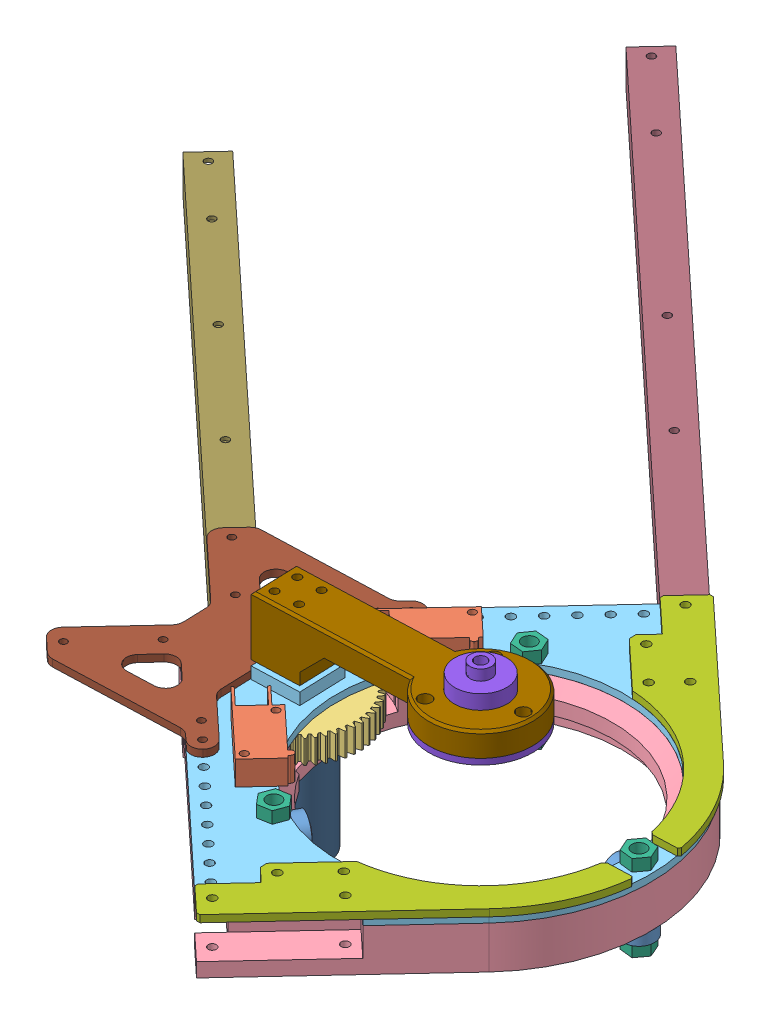
SolidWorks assembly steer_base, configuration ﾃﾞﾌｫﾙﾄ. Lengths in mm.
Overall size (394.9 104.1 424.52).
25 component instances, 13 part files, 51 mates.
Components (placement in the parent):
- Copy of bear_3^steer_base-1: Copy of bear_3^steer_base [ﾃﾞﾌｫﾙﾄ] at (64.7019 -27.57 57.0296) x (-0.998139 0 0.060972) z (0 1 0) size (13 13 5) (virtual)
- Copy of bear_3^steer_base-2: Copy of bear_3^steer_base [ﾃﾞﾌｫﾙﾄ] at (164.1261 -27.57 109.8486) x (-0.435507 0 0.900185) z (0 1 0) size (13 13 5) (virtual)
- Copy of LS^steer_base-1: Copy of LS^steer_base [ﾃﾞﾌｫﾙﾄ] at (50.8347 9.23 168.1143) x (-0.731598 0 -0.681736) z (0 -1 0) size (37.8 18.1 10.3) (virtual)
- Copy of bear_3^steer_base-3: Copy of bear_3^steer_base [ﾃﾞﾌｫﾙﾄ] at (67.3531 -9.07 61.2689) x (-0.432819 -0.859886 0.270672) z (0.530223 0 0.847858) size (13 13 5) (virtual)
- Copy of steer_gear_1^steer_base-1: Copy of steer_gear_1^steer_base [ﾃﾞﾌｫﾙﾄ] at (-26.2181 -27.57 -51.6068) x (0.883116 0 0.469155) z (-0.469155 0 0.883116) size (52 10 52.13) (virtual)
- Copy of base^steer_base-1: Copy of base^steer_base [ﾃﾞﾌｫﾙﾄ] at (99.1665 -14.07 112.1404) x (0.731598 0 0.681736) z (0 1 0) size (160 160 19.28) (virtual)
- Copy of bear_3^steer_base-4: Copy of bear_3^steer_base [ﾃﾞﾌｫﾙﾄ] at (154.1323 -9.07 110.2012) x (0.032581 0.382218 0.923498) z (0.999378 0 -0.035258) size (13 13 5) (virtual)
- Copy of bear_3^steer_base-5: Copy of bear_3^steer_base [ﾃﾞﾌｫﾙﾄ] at (73.363 -9.07 160.7117) x (-0.532711 -0.797577 -0.283002) z (-0.469155 0 0.883116) size (13 13 5) (virtual)
- Copy of bear_3^steer_base-6: Copy of bear_3^steer_base [ﾃﾞﾌｫﾙﾄ] at (68.6714 -27.57 169.5429) x (-0.435507 0 0.900185) z (0 1 0) size (13 13 5) (virtual)
- Copy of base_cover^steer_base-1: Copy of base_cover^steer_base [ﾃﾞﾌｫﾙﾄ] at (99.1665 -4.07 112.1404) x (0.731598 0 0.681736) z (0 1 0) size (160 160 8) (virtual)
- Copy of LS^steer_base-2: Copy of LS^steer_base [ﾃﾞﾌｫﾙﾄ] at (47.0102 -1.07 59.7116) x (-0.681736 0 0.731598) z (0 1 0) size (37.8 18.1 10.3) (virtual)
- Copy of M6_nut^steer_base-1: Copy of M6_nut^steer_base [ﾃﾞﾌｫﾙﾄ] at (164.1261 -1.07 109.8486) x (0.398878 0 0.917004) z (0 1 0) size (11.55 10 5) (virtual)
- Copy of bamper^steer_base-1: Copy of bamper^steer_base [ﾃﾞﾌｫﾙﾄ] at (99.1665 -1.07 112.1404) x (0.731598 0 0.681736) z (0 1 0) size (26 131.43 3) (virtual)
- Copy of bamper^steer_base-2: Copy of bamper^steer_base [ﾃﾞﾌｫﾙﾄ] at (99.1665 1.93 112.1404) x (0.681736 0 -0.731598) z (0 -1 0) size (26 131.43 3) (virtual)
- Copy of slip_ring^steer_base-1: Copy of slip_ring^steer_base [ﾃﾞﾌｫﾙﾄ] at (99.1665 13.73 112.1404) x (0.999378 0 -0.035258) z (0 1 0) size (44 44 33) (virtual)
- Copy of slip_ring_base^steer_base-1: Copy of slip_ring_base^steer_base [ﾃﾞﾌｫﾙﾄ] at (99.1665 21.23 112.1404) x (0.999378 0 -0.035258) z (0 1 0) size (107 44 25) (virtual)
- Copy of M6_nut^steer_base-2: Copy of M6_nut^steer_base [ﾃﾞﾌｫﾙﾄ] at (68.6714 -1.07 169.5429) x (0.642883 0 0.765964) z (0 1 0) size (11.55 10 5) (virtual)
- Copy of M6_nut^steer_base-3: Copy of M6_nut^steer_base [ﾃﾞﾌｫﾙﾄ] at (164.1261 -32.57 109.8486) x (0.398878 0 0.917004) z (0 1 0) size (11.55 10 5) (virtual)
- Copy of M6_nut^steer_base-4: Copy of M6_nut^steer_base [ﾃﾞﾌｫﾙﾄ] at (68.6714 -32.57 169.5429) x (0.398878 0 0.917004) z (0 1 0) size (11.55 10 5) (virtual)
- Copy of M6_nut^steer_base-5: Copy of M6_nut^steer_base [ﾃﾞﾌｫﾙﾄ] at (64.7019 -32.57 57.0296) x (0.398878 0 0.917004) z (0 1 0) size (11.55 10 5) (virtual)
- Copy of M6_nut^steer_base-6: Copy of M6_nut^steer_base [ﾃﾞﾌｫﾙﾄ] at (64.7019 -1.07 57.0296) x (0.995843 0 0.091089) z (0 1 0) size (11.55 10 5) (virtual)
- Copy of M2006^steer_base-1: Copy of M2006^steer_base [ﾃﾞﾌｫﾙﾄ] at (24.7128 -18.57 114.7671) x (0.883116 0 0.469155) z (0 -1 0) size (24.4 24.4 60.8) (virtual)
- Copy of Copy of joint2^steer_base-1: Copy of Copy of joint2^steer_base [ﾃﾞﾌｫﾙﾄ] at (13.9109 -1.07 115.1482) x (-0.731598 0 -0.681736) z (0.681736 0 -0.731598) size (115 3 115) (virtual)
- Copy of Copy of Copy of Copy of pipe180x10^steer_base-1: Copy of Copy of Copy of Copy of pipe180x10^steer_base [ﾃﾞﾌｫﾙﾄ] at (-216.7194 54.9921 -75.6002) x (0 -1 0) z (0.681736 0 -0.731598) size (15 240 15) (virtual)
- Copy of pipe280x15^steer_base-1: Copy of pipe280x15^steer_base [ﾃﾞﾌｫﾙﾄ] at (-126.3246 -16.07 -99.2643) x (0.681736 0 -0.731598) z (0 1 0) size (15 340 15) (virtual)
Mates (geometry in assembly coordinates):
- 一致170: coincident aligned: plane of Copy of bear_3^Assem2_swerve_unit-1 through (64.7019 -22.57 57.0296) normal (0 1 0); plane of Copy of bear_3^Assem2_swerve_unit-2 through (164.1261 -22.57 109.8486) normal (0 1 0)
- 同心円128: concentric anti-aligned: cylinder of Copy of bear_3^Assem2_swerve_unit-1 through (64.7019 -22.57 57.0296) axis (0 -1 0) radius 3; cylinder of Copy of base^steer_base-1 through (64.7019 -22.07 57.0296) axis (0 1 0) radius 3.15
- 一致312: coincident anti-aligned: plane of Copy of bear_3^Assem2_swerve_unit-1 through (64.7019 -27.57 57.0296) normal (0 -1 0); plane of Copy of M6_nut^Assem2_swerve_unit-5 through (64.7019 -27.57 57.0296) normal (0 1 0)
- 同心円166: concentric aligned: cylinder of Copy of bear_3^Assem2_swerve_unit-1 through (64.7019 -22.57 57.0296) axis (0 -1 0) radius 3; cylinder of Copy of M6_nut^Assem2_swerve_unit-5 through (64.7019 -27.57 57.0296) axis (0 -1 0) radius 3
- 同心円123: concentric anti-aligned: cylinder of Copy of bear_3^Assem2_swerve_unit-2 through (164.1261 -22.57 109.8486) axis (0 -1 0) radius 3; cylinder of Copy of base^steer_base-1 through (164.1261 -22.07 109.8486) axis (0 1 0) radius 3.15
- 一致313: coincident anti-aligned: plane of Copy of bear_3^Assem2_swerve_unit-2 through (164.1261 -27.57 109.8486) normal (0 -1 0); plane of Copy of M6_nut^Assem2_swerve_unit-3 through (164.1261 -27.57 109.8486) normal (0 1 0)
- 同心円165: concentric aligned: cylinder of Copy of bear_3^Assem2_swerve_unit-2 through (164.1261 -22.57 109.8486) axis (0 -1 0) radius 3; cylinder of Copy of M6_nut^Assem2_swerve_unit-3 through (164.1261 -27.57 109.8486) axis (0 -1 0) radius 3
- 一致257: coincident anti-aligned: plane of Copy of LS^Assem2_swerve_unit-1 through (50.8347 -1.07 168.1143) normal (0 -1 0); plane of Copy of base_cover^Assem2_swerve_unit-1 through (99.1665 -1.07 112.1404) normal (0 1 0)
- 平行2: parallel aligned: plane of Copy of LS^Assem2_swerve_unit-1 through (50.8347 -1.07 168.1143) normal (-0.681736 0 0.731598); plane of Copy of base^steer_base-1 through (91.8488 -4.07 225.606) normal (-0.681736 0 0.731598)
- 同心円131: concentric aligned: cylinder of Copy of LS^Assem2_swerve_unit-1 through (41.4754 -1.07 141.487) axis (0 1 0) radius 1.55; cylinder of Copy of base_cover^Assem2_swerve_unit-1 through (41.4754 -21.07 141.487) axis (0 1 0) radius 1.7
- 同心円126: concentric aligned: cylinder of Copy of bear_3^Assem2_swerve_unit-3 through (70.0042 -9.07 65.5082) axis (-0.530223 0 -0.847858) radius 3; cylinder of Copy of base^steer_base-1 through (70.5344 -9.07 66.356) axis (-0.530223 0 -0.847858) radius 3
- 一致247: coincident anti-aligned: plane of Copy of bear_3^Assem2_swerve_unit-3 through (67.3531 -9.07 61.2689) normal (-0.530223 0 -0.847858); plane of Copy of base^steer_base-1 through (67.3531 -14.07 61.2689) normal (0.530223 0 0.847858)
- 同心円103: concentric aligned: cylinder of Copy of M2006^Assem2_swerve_unit-1 through (18.9886 -10.57 125.542) axis (0.469155 0 -0.883116) radius 1.5; cylinder of Copy of steer_gear_1^Assem2_swerve_unit-1 through (12.5203 -10.57 137.7178) axis (0.469155 0 -0.883116) radius 1.65
- 同心円106: concentric aligned: cylinder of Copy of M2006^Assem2_swerve_unit-1 through (24.7128 -1.57 114.7671) axis (0 -1 0) radius 3; cylinder of Copy of steer_gear_1^Assem2_swerve_unit-1 through (24.7128 -4.569 114.7671) axis (0 -1 0) radius 3.1
- 同心円124: concentric anti-aligned: cylinder of Copy of base^steer_base-1 through (73.8321 -9.07 159.8286) axis (-0.469155 0 0.883116) radius 3; cylinder of Copy of bear_3^Assem2_swerve_unit-5 through (71.0172 -9.07 165.1273) axis (0.469155 0 -0.883116) radius 3
- 同心円125: concentric anti-aligned: cylinder of Copy of base^steer_base-1 through (153.1329 -9.07 110.2364) axis (0.999378 0 -0.035258) radius 3; cylinder of Copy of bear_3^Assem2_swerve_unit-4 through (159.1292 -9.07 110.0249) axis (-0.999378 0 0.035258) radius 3
- 一致248: coincident anti-aligned: plane of Copy of base^steer_base-1 through (159.1292 -14.07 110.0249) normal (-0.999378 0 0.035258); plane of Copy of bear_3^Assem2_swerve_unit-4 through (159.1292 -9.07 110.0249) normal (0.999378 0 -0.035258)
- 同心円127: concentric anti-aligned: cylinder of Copy of base^steer_base-1 through (68.6714 -22.07 169.5429) axis (0 1 0) radius 3.15; cylinder of Copy of bear_3^Assem2_swerve_unit-6 through (68.6714 -22.57 169.5429) axis (0 -1 0) radius 3
- 同心円130: concentric aligned: cylinder of Copy of M2006^Assem2_swerve_unit-1 through (24.7128 -62.37 114.7671) axis (0 1 0) radius 12.2; cylinder of Copy of base^steer_base-1 through (24.7128 -22.07 114.7671) axis (0 1 0) radius 12.25
- 同心円145: concentric aligned: cylinder of Copy of base^steer_base-1 through (82.4158 -22.071 8.3682) axis (0 1 0) radius 1.75; cylinder of Copy of bamper^Assem2_swerve_unit-2 through (82.4158 -1.07 8.3682) axis (0 1 0) radius 1.75
- 同心円146: concentric aligned: cylinder of Copy of base^steer_base-1 through (111.6797 -22.071 35.6376) axis (0 1 0) radius 1.75; cylinder of Copy of bamper^Assem2_swerve_unit-2 through (111.6797 -1.07 35.6376) axis (0 1 0) radius 1.75
- 同心円147: concentric aligned: cylinder of Copy of M2006^Assem2_swerve_unit-1 through (19.6757 -23.57 106.7124) axis (0 1 0) radius 1.5; cylinder of Copy of base^steer_base-1 through (19.6757 -22.07 106.7124) axis (0 1 0) radius 1.7
- 平行5: parallel aligned: plane of Copy of base^steer_base-1 through (-17.891 -4.07 123.3456) normal (-0.999378 0 0.035258); plane of Copy of slip_ring_base^Assem2_swerve_unit-1 through (14.2193 21.23 115.1373) normal (-0.999378 0 0.035258)
- 一致311: coincident anti-aligned: plane of Copy of bear_3^Assem2_swerve_unit-6 through (68.6714 -27.57 169.5429) normal (0 -1 0); plane of Copy of M6_nut^Assem2_swerve_unit-4 through (68.6714 -27.57 169.5429) normal (0 1 0)
- 同心円167: concentric aligned: cylinder of Copy of bear_3^Assem2_swerve_unit-6 through (68.6714 -22.57 169.5429) axis (0 -1 0) radius 3; cylinder of Copy of M6_nut^Assem2_swerve_unit-4 through (68.6714 -27.57 169.5429) axis (0 -1 0) radius 3
- 一致261: coincident anti-aligned: plane of Copy of base_cover^Assem2_swerve_unit-1 through (99.1665 -1.07 112.1404) normal (0 1 0); plane of Copy of LS^Assem2_swerve_unit-2 through (47.0102 -1.07 59.7116) normal (0 -1 0)
- 同心円132: concentric anti-aligned: cylinder of Copy of base_cover^Assem2_swerve_unit-1 through (47.1498 -21.07 63.6689) axis (0 1 0) radius 1.7; cylinder of Copy of LS^Assem2_swerve_unit-2 through (47.1498 9.23 63.6689) axis (0 -1 0) radius 1.55
- 同心円133: concentric anti-aligned: cylinder of Copy of base_cover^Assem2_swerve_unit-1 through (39.5508 -21.07 86.9323) axis (0 1 0) radius 1.7; cylinder of Copy of LS^Assem2_swerve_unit-2 through (39.5508 9.23 86.9323) axis (0 -1 0) radius 1.55
- 一致263: coincident anti-aligned: plane of Copy of base_cover^Assem2_swerve_unit-1 through (99.1665 -1.07 112.1404) normal (0 1 0); plane of Copy of M6_nut^Assem2_swerve_unit-1 through (164.1261 -1.07 109.8486) normal (0 -1 0)
- 同心円135: concentric aligned: cylinder of Copy of base_cover^Assem2_swerve_unit-1 through (164.1261 -1.07 109.8486) axis (0 -1 0) radius 3.15; cylinder of Copy of M6_nut^Assem2_swerve_unit-1 through (164.1261 3.93 109.8486) axis (0 -1 0) radius 3
- 一致275: coincident anti-aligned: plane of Copy of base_cover^Assem2_swerve_unit-1 through (99.1665 -1.07 112.1404) normal (0 1 0); plane of Copy of bamper^Assem2_swerve_unit-2 through (99.1665 -1.07 112.1404) normal (0 -1 0)
- 距離2: distance = 2.3 mm anti-aligned: plane of Copy of base_cover^Assem2_swerve_unit-1 through (99.1665 3.93 112.1404) normal (0 1 0); plane of Copy of slip_ring_base^Assem2_swerve_unit-1 through (99.1665 6.23 112.1404) normal (0 -1 0)
- 同心円163: concentric aligned: cylinder of Copy of base_cover^Assem2_swerve_unit-1 through (68.6714 -1.07 169.5429) axis (0 -1 0) radius 3.15; cylinder of Copy of M6_nut^Assem2_swerve_unit-2 through (68.6714 3.93 169.5429) axis (0 -1 0) radius 3
- 同心円164: concentric aligned: cylinder of Copy of base_cover^Assem2_swerve_unit-1 through (64.7019 -1.07 57.0296) axis (0 -1 0) radius 3.15; cylinder of Copy of M6_nut^Assem2_swerve_unit-6 through (64.7019 3.93 57.0296) axis (0 -1 0) radius 3
- 一致309: coincident anti-aligned: plane of Copy of base_cover^Assem2_swerve_unit-1 through (99.1665 -1.07 112.1404) normal (0 1 0); plane of Copy of M6_nut^Assem2_swerve_unit-6 through (64.7019 -1.07 57.0296) normal (0 -1 0)
- 一致310: coincident anti-aligned: plane of Copy of base_cover^Assem2_swerve_unit-1 through (99.1665 -1.07 112.1404) normal (0 1 0); plane of Copy of M6_nut^Assem2_swerve_unit-2 through (68.6714 -1.07 169.5429) normal (0 -1 0)
- 同心円168: concentric anti-aligned: cylinder of Copy of base_cover^steer_base-1 through (29.4136 -4.071 160.5918) axis (0 1 0) radius 1.75; cylinder of Copy of Copy of joint2^steer_base-1 through (29.4136 1.93 160.5918) axis (0 -1 0) radius 1.5
- 同心円169: concentric anti-aligned: cylinder of Copy of base_cover^steer_base-1 through (22.0976 -4.071 153.7744) axis (0 1 0) radius 1.75; cylinder of Copy of Copy of joint2^steer_base-1 through (22.0976 1.93 153.7744) axis (0 -1 0) radius 1.5
- 一致314: coincident anti-aligned: plane of Copy of base_cover^steer_base-1 through (99.1665 -1.07 112.1404) normal (0 1 0); plane of Copy of Copy of joint2^steer_base-1 through (13.9109 -1.07 115.1482) normal (0 -1 0)
- 同心円170: concentric anti-aligned: cylinder of Copy of base_cover^steer_base-1 through (94.2602 -4.071 193.6813) axis (0 1 0) radius 1.75; cylinder of Copy of bamper^steer_base-1 through (94.2602 1.93 193.6813) axis (0 -1 0) radius 1.75
- 同心円171: concentric anti-aligned: cylinder of Copy of base_cover^steer_base-1 through (107.8949 -4.071 179.0494) axis (0 1 0) radius 1.75; cylinder of Copy of bamper^steer_base-1 through (107.8949 1.93 179.0494) axis (0 -1 0) radius 1.75
- 一致315: coincident anti-aligned: plane of Copy of base_cover^steer_base-1 through (99.1665 -1.07 112.1404) normal (0 1 0); plane of Copy of bamper^steer_base-1 through (99.1665 -1.07 112.1404) normal (0 -1 0)
- 同心円172: concentric aligned: cylinder of Copy of base^steer_base-1 through (50.695 -22.071 164.157) axis (0 1 0) radius 1.7; cylinder of Copy of base_cover^steer_base-1 through (50.695 -21.07 164.157) axis (0 1 0) radius 1.7
- 同心円173: concentric aligned: cylinder of Copy of base^steer_base-1 through (41.4754 -22.071 141.487) axis (0 1 0) radius 1.7; cylinder of Copy of base_cover^steer_base-1 through (41.4754 -21.07 141.487) axis (0 1 0) radius 1.7
- 一致316: coincident anti-aligned: plane of Copy of base^steer_base-1 through (99.1665 -4.07 112.1404) normal (0 1 0); plane of Copy of base_cover^steer_base-1 through (99.1665 -4.07 112.1404) normal (0 -1 0)
- 同心円174: concentric anti-aligned: cylinder of Copy of Copy of joint2^steer_base-1 through (-16.9346 1.93 100.3166) axis (0 -1 0) radius 1.5; cylinder of Copy of Copy of Copy of Copy of pipe180x10^steer_base-1 through (-16.9346 -16.07 100.3166) axis (0 1 0) radius 1.6
- 同心円175: concentric anti-aligned: cylinder of Copy of Copy of joint2^steer_base-1 through (-38.8825 1.93 79.8645) axis (0 -1 0) radius 1.5; cylinder of Copy of Copy of Copy of Copy of pipe180x10^steer_base-1 through (-38.8825 -16.07 79.8645) axis (0 1 0) radius 1.6
- 一致317: coincident anti-aligned: plane of Copy of Copy of joint2^steer_base-1 through (13.9109 -1.07 115.1482) normal (0 -1 0); plane of Copy of Copy of Copy of Copy of pipe180x10^steer_base-1 through (-183.7471 -1.07 -65.3783) normal (0 1 0)
- 同心円71: concentric aligned: cylinder of Copy of pipe280x15^steer_base-1 through (111.6797 -1.07 35.6376) axis (0 1 0) radius 1.6; cylinder of Copy of bamper^steer_base-2 through (111.6797 -1.07 35.6376) axis (0 1 0) radius 1.75
- 同心円72: concentric aligned: cylinder of Copy of pipe280x15^steer_base-1 through (82.4158 -1.07 8.3682) axis (0 1 0) radius 1.6; cylinder of Copy of bamper^steer_base-2 through (82.4158 -1.07 8.3682) axis (0 1 0) radius 1.75
- 一致318: coincident anti-aligned: plane of Copy of base^steer_base-1 through (99.1665 -16.07 112.1404) normal (0 1 0); plane of Copy of pipe280x15^steer_base-1 through (-126.3246 -16.07 -99.2643) normal (0 -1 0)
